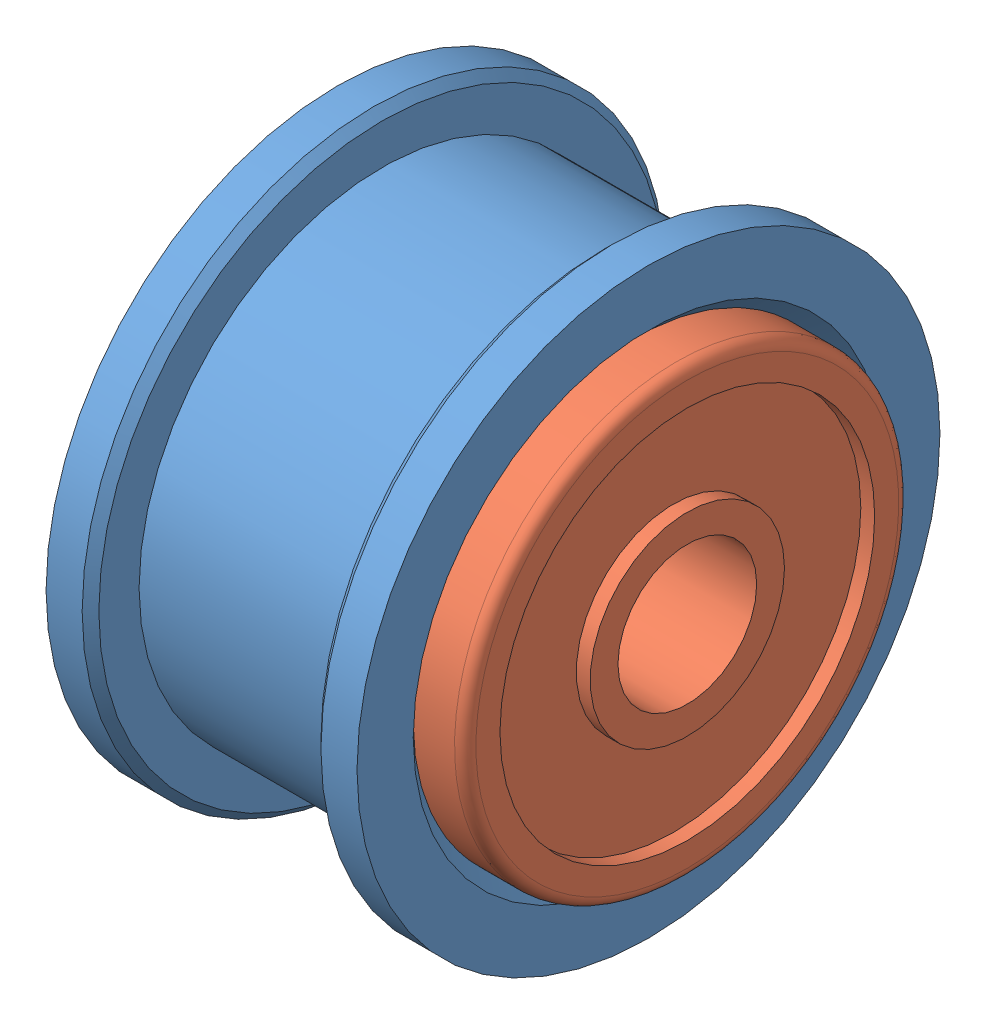
SolidWorks assembly idler pulley, configuration Default. Lengths in mm.
Overall size (12.6 21 21).
4 component instances, 3 part files, 0 mates.
Components (placement in the parent):
- B17023-1: B17023 [Default] at origin size (11.2 21 21)
- BEARING_5_16_5-1: BEARING_5_16_5 [Default] at (-1.5 0 0) x (0 1 0) z (0 0 1) size (16 5 16)
- B18026-1: B18026 [Default] at (2 0 0) x (0 1 0) z (0 0 1) size (10 1 10)
- BEARING_5_16_5-2: BEARING_5_16_5 [Default] at (4.5 0 0) x (0 1 0) z (0 0 1) size (16 5 16)
